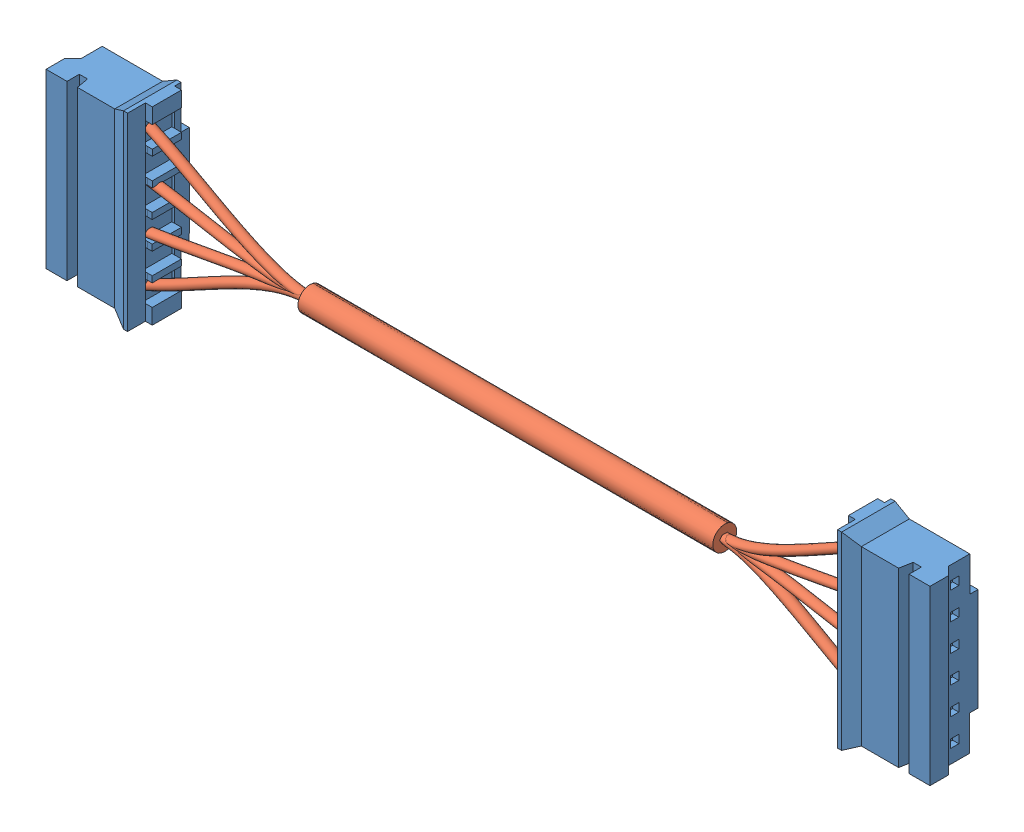
SolidWorks assembly 040M07C01.0P29A Left extruder Cable, configuration flatten route. Lengths in mm.
Overall size (1000 1000 0).
6 component instances, 5 part files, 9 mates.
Components (placement in the parent):
- PHR-6_PRUEBA-1: PHR-6_PRUEBA [Predeterminado] at (43.6419 -2.2939 2.8002) x (-0.000324 -1 0) z (1 -0.000324 0) size (13.8 4.5 16.15)
- PHR-6_PRUEBA-2: PHR-6_PRUEBA [Predeterminado] at (-14.392 2.2322 2.4056) x (0.000184 1 0) z (-1 0.000184 0) size (13.8 4.5 16.15)
- Cable^040M07C01.0P29A Left extruder Cable-1: Cable^040M07C01.0P29A Left extruder Cable [Predeterminado] at origin size (21.01 35.58 26.79) (suppressed, hidden, virtual)
- Flattened_Cable^040M07C01.0P29A Left extruder Cable-1: Flattened_Cable^040M07C01.0P29A Left extruder Cable [Predeterminado] at origin (suppressed, hidden, virtual)
- Flattened_Cable_1^040M07C01.0P29A Left extruder Cable-1: Flattened_Cable_1^040M07C01.0P29A Left extruder Cable [Predeterminado] at origin (virtual)
- Flattened_Cable_2^040M07C01.0P29A Left extruder Cable-1: Flattened_Cable_2^040M07C01.0P29A Left extruder Cable [Predeterminado] at origin (suppressed, hidden, virtual)
Mates (geometry in assembly coordinates):
- Coincidente1: coincident anti-aligned: plane of PHR-6_PRUEBA-1; plane of ? through (-15.0244 -18.402 -39.6102) normal (0 -1 0)
- Coincidente2: coincident aligned: plane of PHR-6_PRUEBA-1; plane of ? through (-15.6244 -22.652 -26.3602) normal (-1 0 0)
- Coincidente3: coincident anti-aligned: plane of PHR-6_PRUEBA-1; plane of ? through (-15.0244 -22.652 -39.6102) normal (0 0 1)
- Coincidente6: coincident anti-aligned: plane of PHR-6_PRUEBA-2 through (-24.1803 -71.3 38.45) normal (-1 0 0); plane of ? through (-24.1803 -71.9 38.45) normal (1 0 0)
- Coincidente7: coincident aligned: plane of PHR-6_PRUEBA-2; plane of ? through (-19.9303 -85.15 37.85) normal (0 0 -1)
- Coincidente8: coincident anti-aligned: plane of PHR-6_PRUEBA-2; plane of ? through (-19.9303 -71.9 38.45) normal (0 -1 0)
- Coincidente10: coincident aligned: plane of PHR-6_PRUEBA-2; plane of ? through (-31.8244 -45.702 -50.2102) normal (0 0 1)
- Coincidente11: coincident anti-aligned: plane of PHR-6_PRUEBA-2; plane of ? through (-36.0744 -58.952 -50.8102) normal (1 0 0)
- Coincidente12: coincident anti-aligned: plane of PHR-6_PRUEBA-2; plane of ? through (-31.8244 -46.352 -50.8102) normal (0 -1 0)
